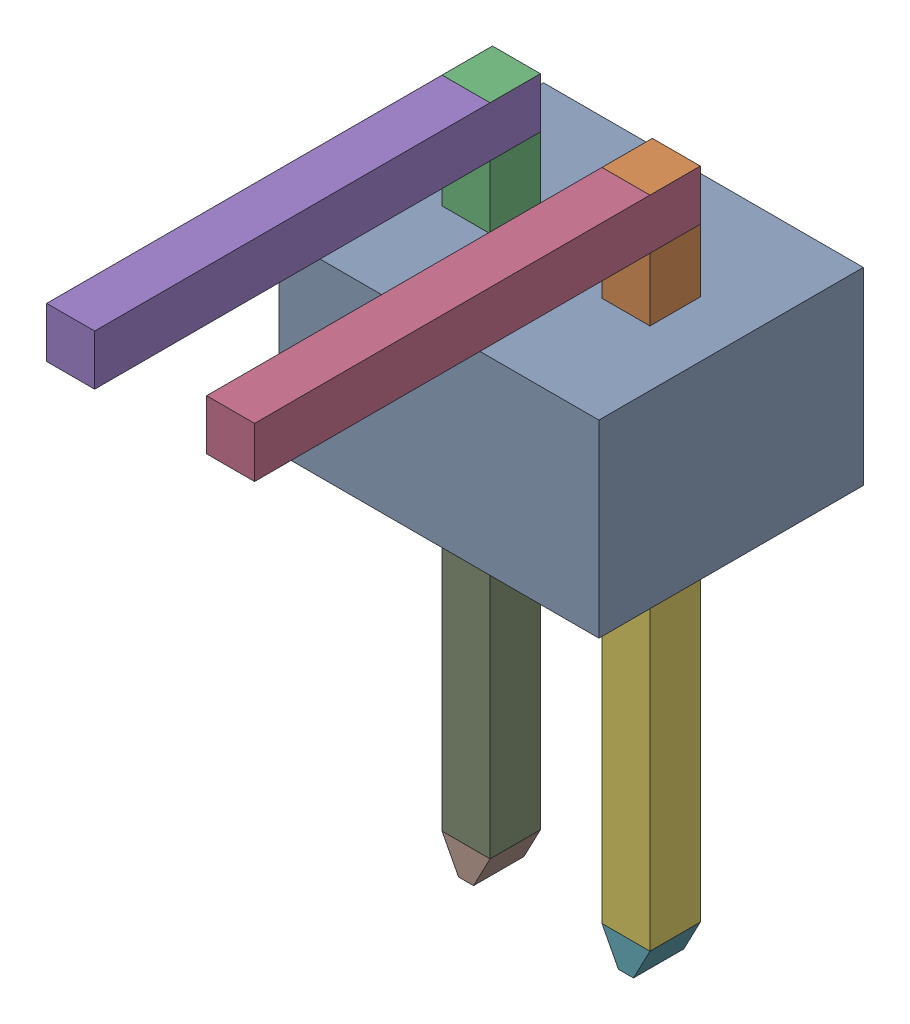
SolidWorks assembly JP1, configuration Default. Lengths in mm.
Overall size (2.54 5.45 4.39).
18 component instances, 5 part files, 0 mates.
Components (placement in the parent):
- 1737249824-1: 1737249824 [Default] at (4.63 4 -3.744) size (2.54 1.5 2.1)
  - Extruded-3-1: Extruded-3 [Default] at origin size (2.54 1.5 2.1)
- 1737249960-1: 1737249960 [Default] at (5.265 5.2 -2.894) size (0.38 0.9 0.4)
  - Extruded-4-1: Extruded-4 [Default] at origin size (0.38 0.9 0.4)
- 1737249960-2: 1737249960 [Default] at (3.995 5.2 -2.894) size (0.38 0.9 0.4)
  - Extruded-4-1: Extruded-4 [Default] at origin size (0.38 0.9 0.4)
- 1737252408-1: 1737252408 [Default] at (5.265 5.45 -2.894) size (0.38 0.4 3.54)
  - Extruded-5-1: Extruded-5 [Default] at origin size (0.38 0.4 3.54)
- 1737252408-2: 1737252408 [Default] at (3.995 5.45 -2.894) size (0.38 0.4 3.54)
  - Extruded-5-1: Extruded-5 [Default] at origin size (0.38 0.4 3.54)
- 1737252544-1: 1737252544 [Default] at (5.265 1.85 -2.894) size (0.38 2.8 0.4)
  - Extruded-6-1: Extruded-6 [Default] at origin size (0.38 2.8 0.4)
- 1737252680-1: 1737252680 [Default] at (5.265 0.325 -2.894) size (0.38 0.25 0.4)
  - Extruded-7-1: Extruded-7 [Default] at origin size (0.38 0.25 0.4)
- 1737252680-2: 1737252680 [Default] at (3.995 0.325 -2.894) size (0.38 0.25 0.4)
  - Extruded-7-1: Extruded-7 [Default] at origin size (0.38 0.25 0.4)
- 1737252544-2: 1737252544 [Default] at (3.995 1.85 -2.894) size (0.38 2.8 0.4)
  - Extruded-6-1: Extruded-6 [Default] at origin size (0.38 2.8 0.4)
